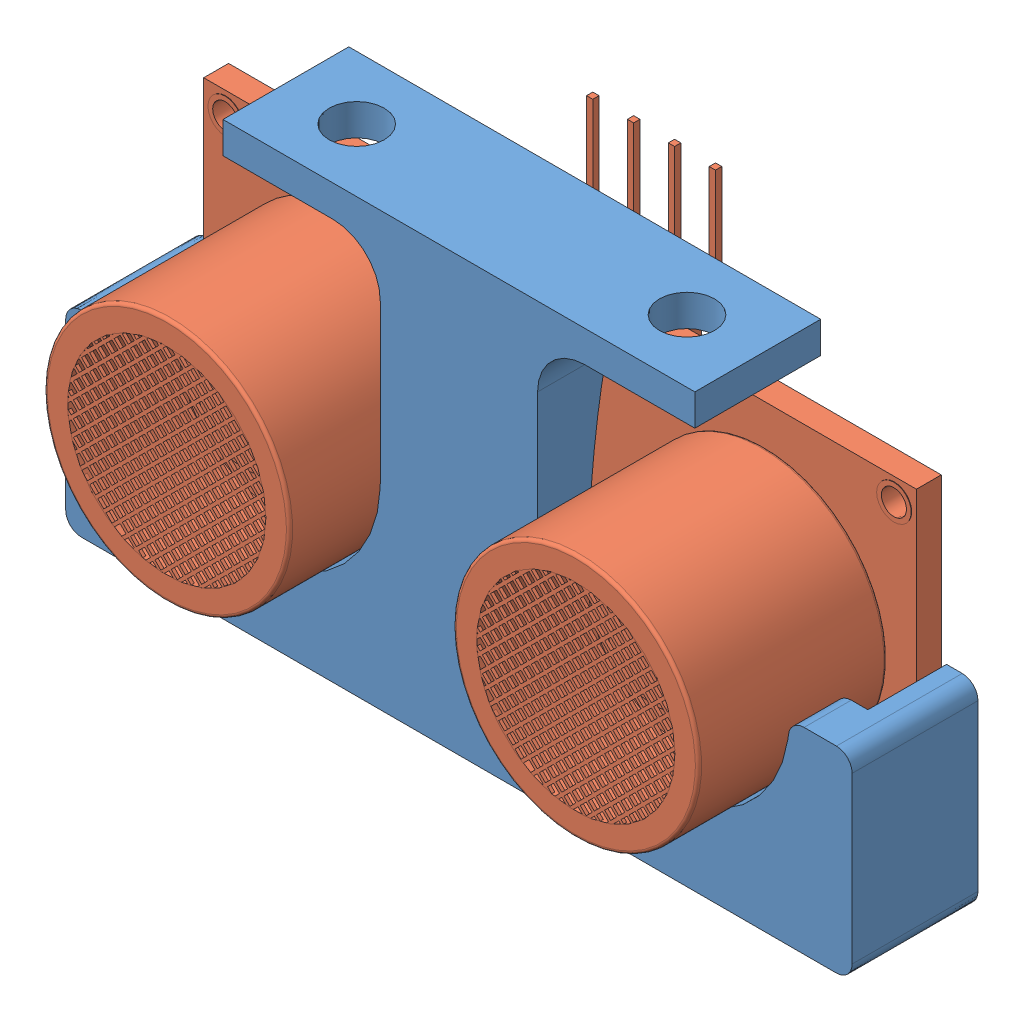
SolidWorks assembly hc-sr04_assembly, configuration Défaut. Lengths in mm.
Overall size (50 28.16 18.18).
2 component instances, 2 part files, 3 mates.
Components (placement in the parent):
- hc-sr04_mount-1: hc-sr04_mount [Défaut] at (-2.0029 8.4887 50) size (50 27.5 8)
- hc-sr04-1: hc-sr04 [Predeterminado] at (7.073 53.7987 43.9598) x (1 0 0) z (0 -1 0) size (45.31 18.18 25.91)
Mates (geometry in assembly coordinates):
- Coaxiale1: concentric: cylinder of hc-sr04_mount-1 through (10.9971 8.4887 53) axis (0 0 -1) radius 8; cylinder of hc-sr04-1 through (10.9971 8.4887 46.57) axis (0 0 1) radius 7.8
- Coaxiale2: concentric: cylinder of hc-sr04_mount-1 through (-15.0029 8.4887 53) axis (0 0 -1) radius 8; cylinder of hc-sr04-1 through (-15.0029 8.4887 46.57) axis (0 0 1) radius 7.8
- Coïncidente1: coincident: plane of hc-sr04_mount-1 through (10.9971 8.4887 50) normal (0 0 -1); plane of hc-sr04-1 through (-5.1829 0.9837 50) normal (0 0 1)
